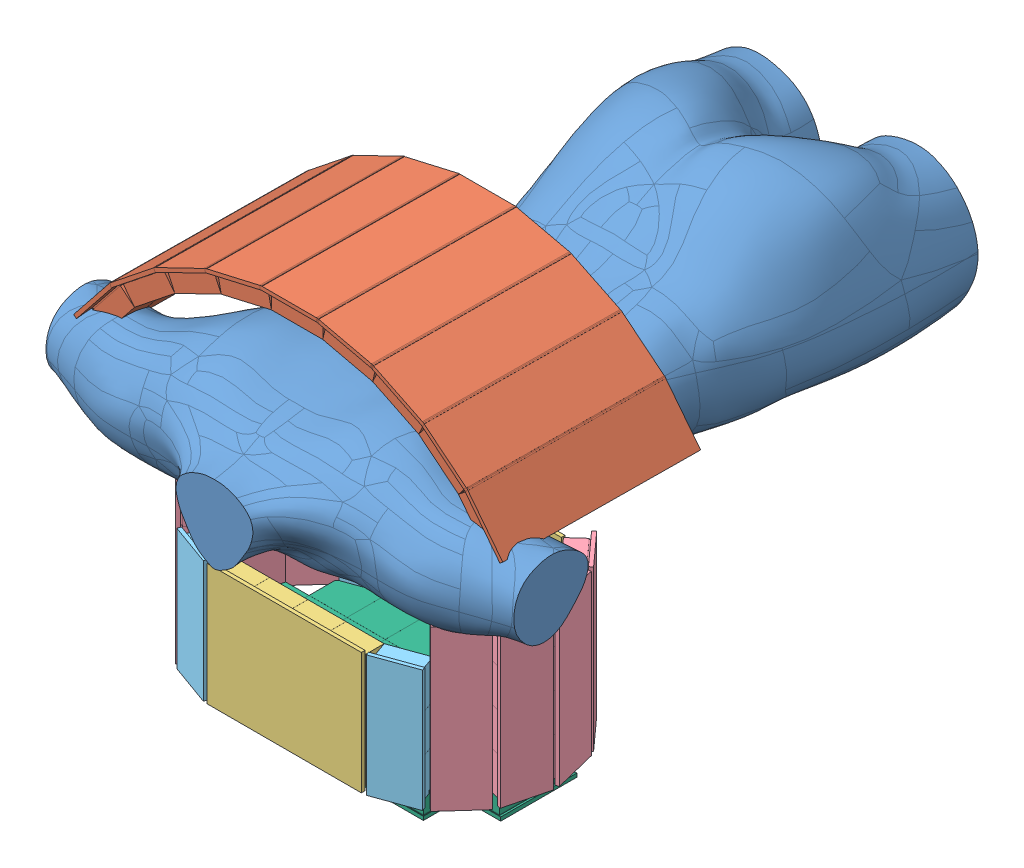
SolidWorks assembly Assem1, configuration Default. Lengths in mm.
Overall size (701.61 752.42 899.3).
29 component instances, 6 part files, 0 mates.
Components (placement in the parent):
- woman body-1: woman body [Default] at (196.8565 656.3794 482.852) size (701.61 331.12 899.3)
- CshapedDetector1-2: CshapedDetector1 [Default] at (462.29 915.1834 874.4586) x (-0.900926 0.433957 -0.003787) z (0 0.008727 0.999962) size (527.59 312.86 270)
  - 5Detector-1: 5Detector [Default] at (91.8512 126.8436 184.2598) size (80 32 270)
  - 5Detector-2: 5Detector [Default] at (168.0955 135.4362 184.2598) x (0.974917 0.22257 0) z (0 0 1) size (80 32 270)
  - 5Detector-4: 5Detector [Default] at (240.515 160.783 184.2598) x (0.900926 0.433974 0) z (0 0 1) size (80 32 270)
  - 5Detector-5: 5Detector [Default] at (305.4764 201.6123 184.2598) x (0.781738 0.623607 0) z (0 0 1) size (80 32 270)
  - 5Detector-6: 5Detector [Default] at (359.7211 255.8759 184.2598) x (0.623334 0.781956 0) z (0 0 1) size (80 32 270)
  - 5Detector-7: 5Detector [Default] at (400.5278 320.8517 184.2598) x (0.433659 0.901077 0) z (0 0 1) size (80 32 270)
  - 5Detector-8: 5Detector [Default] at (15.6069 135.4362 184.2598) x (0.974917 -0.22257 0) z (0 0 1) size (80 32 270)
  - 5Detector-9: 5Detector [Default] at (-56.8125 160.783 184.2598) x (0.900926 -0.433974 0) z (0 0 1) size (80 32 270)
  - 5Detector-10: 5Detector [Default] at (425.8492 393.2799 184.2598) x (0.222229 0.974994 0) z (0 0 1) size (80 32 270)
- detectorassem-1: detectorassem [Default] at (165.9838 443.4414 957.2963) x (1 0 0) z (0 -1 0) size (517.67 317.54 241.94)
  - 52mmTOPBOTTOM-1: 52mmTOPBOTTOM [Default] at (-69.8528 -35.4842 8.7442) size (210.55 32 166)
  - SideDetector-1: SideDetector [Default] at (215.9367 233.9438 -54.2197) x (-0.242515 0.970148 0) z (0 0 1) size (268 155.36 218)
    - 52mmX4-1: 52mmX4 [Default] at (-99.1405 6.5957 36.9639) size (60 32 218)
    - 52mmX4-2: 52mmX4 [Default] at (-35.1412 22.594 36.9639) x (0.882373 0.47055 0) z (0 0 1) size (60 32 218)
    - 52mmX4-3: 52mmX4 [Default] at (-163.1399 22.594 36.9639) x (0.882373 -0.47055 0) z (0 0 1) size (60 32 218)
    - 52mmX4-4: 52mmX4 [Default] at (-212.0831 66.8254 36.9639) x (0.557166 -0.830401 0) z (0 0 1) size (60 32 218)
    - 52mmX3-1: 52mmX3 [Default] at (-234.4563 128.8843 62.9639) x (0.100883 -0.994898 0) z (0 0 1) size (60 32 166)
    - 52mmX3-2: 52mmX3 [Default] at (13.802 66.8254 62.9639) x (0.557166 0.830401 0) z (0 0 1) size (60 32 166)
  - SideDetector-2: SideDetector [Default] at (-199.3424 -27.5859 -54.2197) x (0.242515 -0.970148 0) z (0 0 1) size (268 155.36 218)
    - 52mmX4-1: 52mmX4 [Default] at (-99.1405 6.5957 36.9639) size (60 32 218)
    - 52mmX4-2: 52mmX4 [Default] at (-35.1412 22.594 36.9639) x (0.882373 0.47055 0) z (0 0 1) size (60 32 218)
    - 52mmX4-3: 52mmX4 [Default] at (-163.1399 22.594 36.9639) x (0.882373 -0.47055 0) z (0 0 1) size (60 32 218)
    - 52mmX4-4: 52mmX4 [Default] at (-212.0831 66.8254 36.9639) x (0.557166 -0.830401 0) z (0 0 1) size (60 32 218)
    - 52mmX3-1: 52mmX3 [Default] at (-234.4563 128.8843 62.9639) x (0.100883 -0.994898 0) z (0 0 1) size (60 32 166)
    - 52mmX3-2: 52mmX3 [Default] at (13.802 66.8254 62.9639) x (0.557166 0.830401 0) z (0 0 1) size (60 32 166)
  - 52mmTOPBOTTOM-2: 52mmTOPBOTTOM [Default] at (86.4472 241.8421 8.7442) x (-1 0 0) z (0 0 1) size (210.55 32 166)
  - 52mmAnterior-2: 52mmAnterior [Default] at (34.3203 129.1897 115.6812) x (1 0 0) z (0 1 0) size (423.62 32 209.26)
